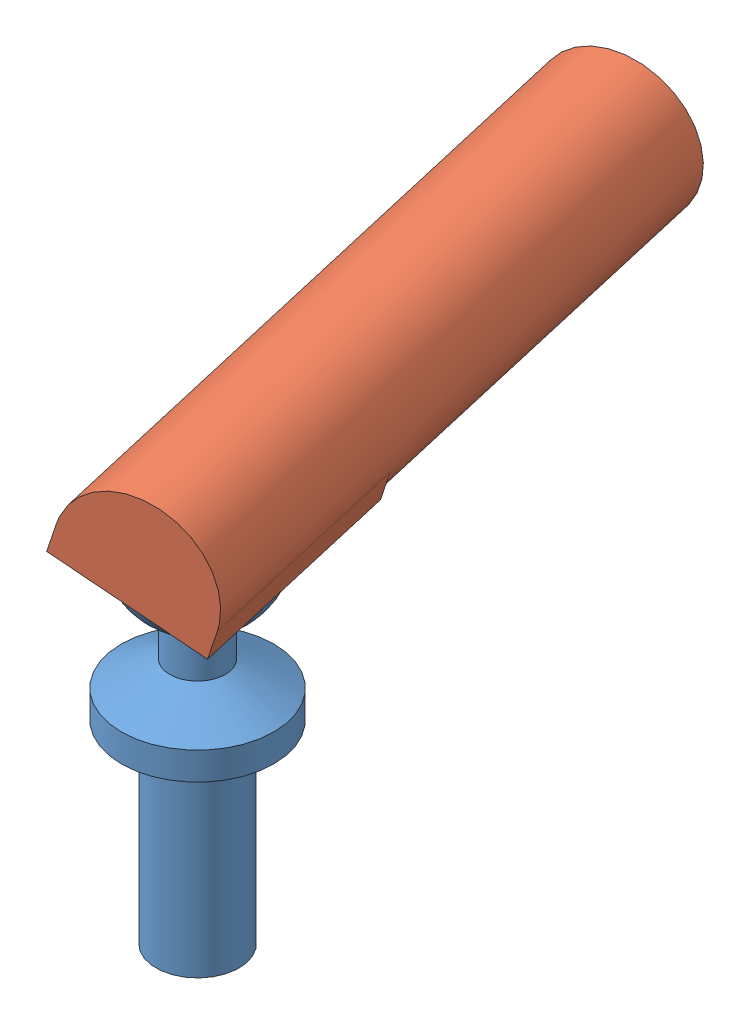
SolidWorks assembly Ball joint assy, configuration Default. Lengths in mm.
Overall size (10.95 17.24 23.35).
2 component instances, 2 part files, 1 mates.
Components (placement in the parent):
- Ball-1: Ball [Default] at origin size (5.5 15.11 5.5)
- Joint-1: Joint [Default] at (-1.3523 13.7919 -7.8662) x (0.932864 -0.296283 -0.204891) z (-0.294339 -0.954837 0.040624) size (5.1 22.6 5.1)
Mates (geometry in assembly coordinates):
- Concentric1: concentric: sphere of Ball-1; sphere of Joint-1
